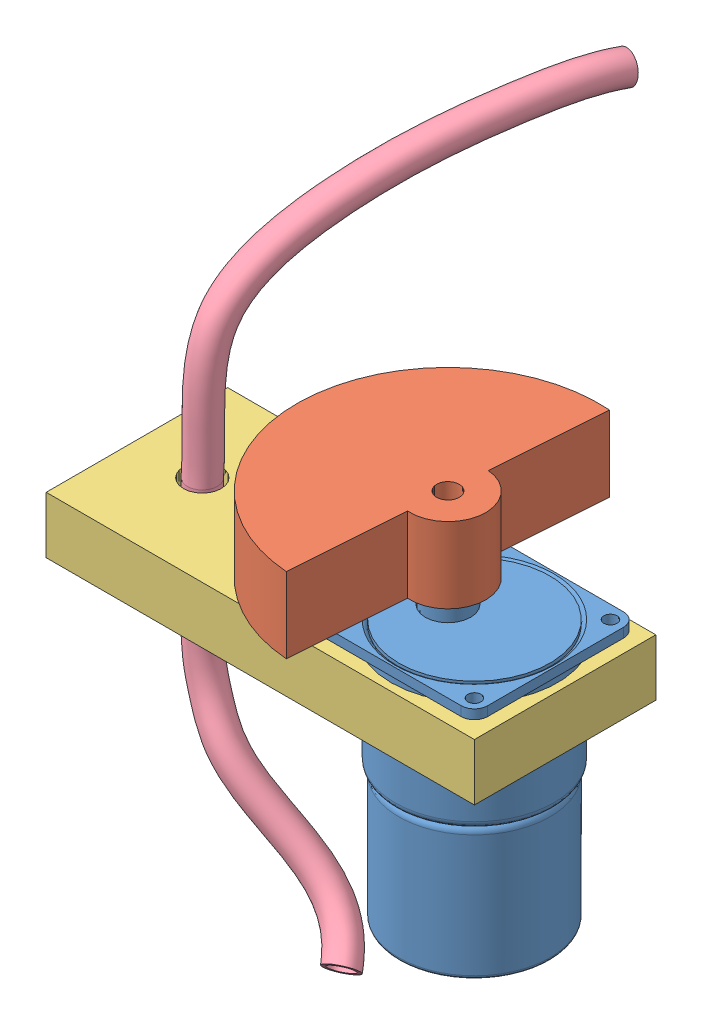
SolidWorks assembly Agitator-Assembly, configuration Default. Lengths in mm.
Overall size (113.32 157.84 135.03).
4 component instances, 4 part files, 8 mates.
Components (placement in the parent):
- TG06-DCMotor-1: TG06-DCMotor [Default] at (-45.5 66 -2.5) x (0 0 -1) z (0 1 0) size (43 43 89)
- Agitator-Disk-1: Agitator-Disk [Default] at (-49.8937 74.5 -62.0398) x (-0.071234 0 0.99746) z (0 1 0) size (80 50 20)
- Agitator-Platform-1: Agitator-Platform [Default] at (0 65 0) x (-1 0 0) z (0 0 1) size (113.32 15 48)
- Pipe-1: Pipe [Default] at (-96 50 -24) x (-0.201539 0 0.97948) z (-0.97948 0 -0.201539) size (99.73 157.84 47.07)
Mates (geometry in assembly coordinates):
- Concentric1: concentric: cylinder of TG06-DCMotor-1 through (-31 89 -24) axis (0 -1 0) radius 3; cylinder of Agitator-Disk-1 through (-31 102.9853 -24) axis (0 -1 0) radius 3
- Distance1: distance = 0.5 mm: plane of TG06-DCMotor-1 through (-31 74 -24) normal (0 1 0); plane of Agitator-Disk-1 through (-31 74.5 -24) normal (0 -1 0)
- Distance2: distance = 1 mm: plane of Agitator-Platform-1 through (0 65 0) normal (0 1 0); plane of TG06-DCMotor-1 through (-42 66 -6) normal (0 -1 0)
- Distance3: distance = 2.5 mm: plane of Agitator-Platform-1 through (0 50 0) normal (0 0 1); plane of TG06-DCMotor-1 through (-42 68.5 -2.5) normal (0 0 1)
- Distance4: distance = 2.5 mm: plane of Agitator-Platform-1 through (0 50 0) normal (1 0 0); plane of TG06-DCMotor-1 through (-2.5 68.5 -6) normal (1 0 0)
- Coincident1: coincident: plane of assembly through (0 0 0) normal (0 1 0); plane of TG06-DCMotor-1 through (-24 0 -24) normal (0 -1 0); plane of assembly
- Coincident2: coincident: plane of assembly through (0 0 0) normal (1 0 0); plane of Agitator-Platform-1 through (0 50 0) normal (1 0 0); plane of assembly
- Coincident3: coincident: plane of assembly through (0 0 0) normal (0 0 1); plane of Agitator-Platform-1 through (0 50 0) normal (0 0 1); plane of assembly
